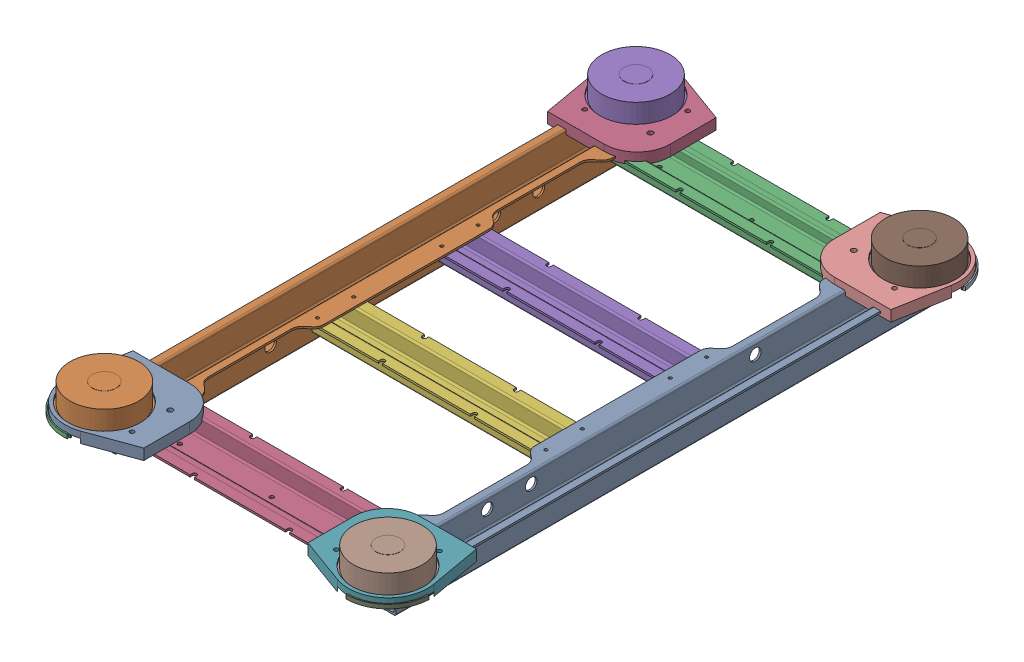
SolidWorks assembly Wii Board Frame, configuration Default. Lengths in mm.
Overall size (314.24 42.99 516.77).
22 component instances, 7 part files, 4 mates.
Components (placement in the parent):
- Large-1: Large [Default] at (206.8235 207.6746 101.5413) x (0 0 -1) z (1 0 0) size (459.91 23.26 57.4)
- Large-2: Large [Default] at (-21.1765 207.6746 544.1917) x (0 0 1) z (-1 0 0) size (459.91 23.26 57.4)
- Medium-1: Medium [Default] at (-8.4415 214.2346 125.5838) x (-1 0 0) z (0 0 -1) size (202 15.14 49.18)
- Medium-2: Medium [Default] at (193.5585 214.2346 520.1492) size (202 15.14 49.18)
- Small-1: Small [Default] at (194.2535 214.2346 271.9988) size (203.2 15.14 37.7)
- Small-2: Small [Default] at (194.2535 214.2346 373.7342) size (203.2 15.14 37.7)
- Foot Assembly V1-1: Foot Assembly V1 [Default] at (256.9309 269.6165 563.5545) x (0 0 -1) z (-1 0 0) size (89.12 26.84 90.12)
  - Foot Holder V1-1: Foot Holder V1 [Default] at (15.5856 30.9628 39.4334) size (80.15 12.25 81.15)
  - Foot scale-1: Foot scale [Default] at (23.5939 47.331 48.2789) x (0.888733 0 -0.458424) z (-0.458424 0 -0.888733) size (61.3 17.29 61.3)
  - Rubber Curve scaled-1: Rubber Curve scaled [Default] at (45.353 41.8919 4.4375) x (0.004822 0 0.999988) z (0.999988 0 -0.004822) size (34.64 3.26 34.69)
- Foot Assembly V2 Mirror-1: Foot Assembly V2 Mirror [Default] at (261.6868 189.3309 79.0969) x (0 0 1) z (-1 0 0) size (85.28 26.84 82.7)
  - Foot Holder V2 mirror-1: Foot Holder V2 mirror [Default] at (18.6675 26.4646 44.1893) size (80.15 12.25 81.15)
  - Foot scale-1: Foot scale [Default] at (26.6758 32.9546 53.0349) size (61.3 17.29 61.3)
  - Rubber Curve scaled-1: Rubber Curve scaled [Default] at (-14.4552 37.6035 79.5591) x (0.99427 0 -0.106896) z (0.106896 0 0.99427) size (34.64 3.26 34.69)
- Foot Assembly V2 Mirror-2: Foot Assembly V2 Mirror [Default] at (-76.0398 189.3309 566.6364) x (0 0 -1) z (1 0 0) size (85.28 26.84 82.7)
  - Foot Holder V2 mirror-1: Foot Holder V2 mirror [Default] at (18.6675 26.4646 44.1893) size (80.15 12.25 81.15)
  - Foot scale-1: Foot scale [Default] at (26.6758 32.9546 53.0349) size (61.3 17.29 61.3)
  - Rubber Curve scaled-1: Rubber Curve scaled [Default] at (-14.4552 37.6035 79.5591) x (0.99427 0 -0.106896) z (0.106896 0 0.99427) size (34.64 3.26 34.69)
- Foot Assembly V1-3: Foot Assembly V1 [Default] at (-71.2838 269.6165 82.1788) x (0 0 1) z (1 0 0) size (89.12 26.84 90.12)
  - Foot Holder V1-1: Foot Holder V1 [Default] at (15.5856 30.9628 39.4334) size (80.15 12.25 81.15)
  - Foot scale-1: Foot scale [Default] at (23.5939 47.331 48.2789) x (0.888733 0 -0.458424) z (-0.458424 0 -0.888733) size (61.3 17.29 61.3)
  - Rubber Curve scaled-1: Rubber Curve scaled [Default] at (45.353 41.8919 4.4375) x (0.004822 0 0.999988) z (0.999988 0 -0.004822) size (34.64 3.26 34.69)
Mates (geometry in assembly coordinates):
- Coincident15: coincident: line of Large-2 through (6.7685 229.3746 154.3328) axis (0 0 -1); plane of Medium-1 through (193.5585 229.3746 142.0638) normal (0 1 0)
- Coincident16: coincident: line of Large-2 through (6.7685 229.3746 506.3713) axis (0 0 -1); plane of Medium-2 through (-8.4415 229.3746 503.6692) normal (0 1 0)
- Coincident17: coincident: line of Large-2 through (6.7685 229.3746 390.2566) axis (0 0 -1); plane of Small-1 through (-8.9465 229.3746 282.8288) normal (0 1 0)
- Coincident19: coincident: line of Large-2 through (6.7685 229.3746 390.2566) axis (0 0 -1); plane of Small-2 through (-8.9465 229.3746 384.5642) normal (0 1 0)
